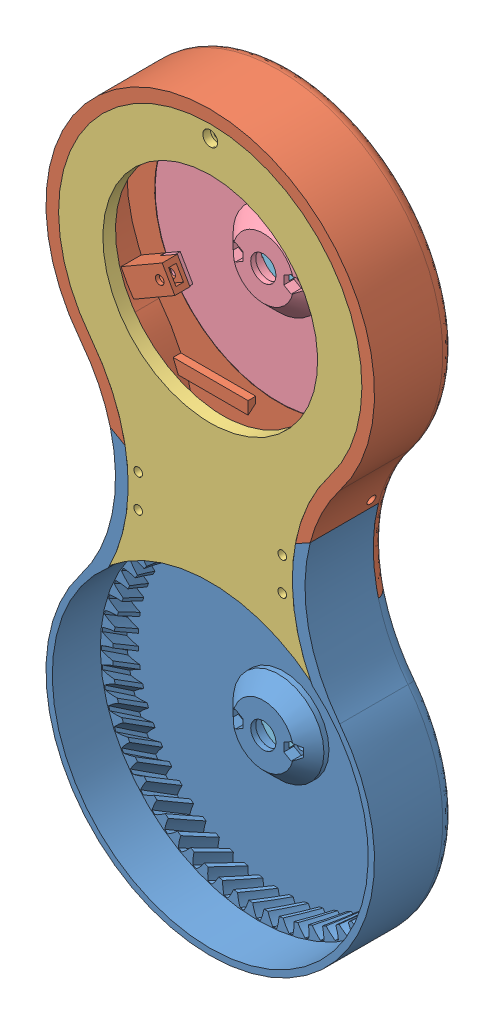
SolidWorks assembly ART2_1, configuration Predeterminado. Lengths in mm.
Overall size (130 290 32.44).
6 component instances, 5 part files, 32 mates.
Components (placement in the parent):
- Art2BodyA_Splitted_A-1: Art2BodyA_Splitted_A [Predeterminado] at (-59.4369 13.7484 145.2842) size (130 161.27 32)
- Art2BodyA_Splitted_B-1: Art2BodyA_Splitted_B [Predeterminado] at (-59.4369 93.7484 145.2842) x (1 0 0) z (0 -1 0) size (130 32.44 161.71)
- Art2BodyACover2-1: Art2BodyACover2 [Predeterminado] at (-59.4369 13.7484 177.2842) x (-1 0 0) z (0 -1 0) size (120 7 171.15)
- Art2BodyAWindow-1: Art2BodyAWindow [Predeterminado] at (-59.4369 173.7484 145.2842) x (-1 0 0) z (0 1 0) size (97.6 11 97.6)
- CommonBearingFix-1: CommonBearingFix [Predeterminado] at (-59.4369 173.7484 149.2842) x (1 0 0) z (0 0 -1) size (30 15.8 4)
- CommonBearingFix-2: CommonBearingFix [Predeterminado] at (-59.4369 13.7484 149.2842) x (1 0 0) z (0 0 -1) size (30 15.8 4)
Mates (geometry in assembly coordinates):
- Concéntrica1: concentric aligned: cylinder of Art2BodyA_Splitted_A-1 through (-87.9369 100.2484 145.2842) axis (0 0 -1) radius 1.7; cylinder of Art2BodyA_Splitted_B-1 through (-87.9369 100.2484 156.7842) axis (0 0 -1) radius 1.7
- Concéntrica2: concentric aligned: cylinder of Art2BodyA_Splitted_A-1 through (-30.9369 87.2484 145.2842) axis (0 0 -1) radius 1.7; cylinder of Art2BodyA_Splitted_B-1 through (-30.9369 87.2484 148.1842) axis (0 0 -1) radius 2.95
- Coincidente1: coincident anti-aligned: plane of Art2BodyA_Splitted_A-1 through (-59.4369 102.6007 150.2842) normal (0 0 -1); plane of Art2BodyA_Splitted_B-1 through (-8.2022 53.7484 150.2842) normal (0 0 1)
- Concéntrica5: concentric aligned: cylinder of Art2BodyA_Splitted_B-1 through (-98.4081 151.2484 150.2842) axis (0 0 1) radius 1.7; cylinder of hexagon nut_3_jis-1 through (-98.4081 151.2484 153.7842) axis (0 0 1) radius 1.25
- Paralelo5: parallel aligned: plane of Art2BodyA_Splitted_B-1 through (-98.4081 154.5984 156.7842) normal (0.5 -0.866025 0); plane of hexagon nut_3_jis-1 through (-98.4081 148.073 153.7842) normal (0.5 -0.866025 0)
- Coincidente11: coincident anti-aligned: plane of Art2BodyA_Splitted_B-1 through (9.8451 213.7484 153.7842) normal (0 0 1); plane of hexagon nut_3_jis-1 through (-103.9081 151.2484 153.7842) normal (0 0 -1)
- Concéntrica22: concentric aligned: cylinder of Art2BodyA_Splitted_B-1 through (-59.4369 173.7484 150.2842) axis (0 0 1) radius 60; cylinder of Art2BodyACover2-1 through (-59.4369 173.7484 172.2842) axis (0 0 1) radius 42.5
- Coincidente31: coincident aligned: plane of Art2BodyA_Splitted_B-1 through (-8.2022 53.7484 177.2842) normal (0 0 1); plane of Art2BodyACover2-1 through (-110.6718 53.7486 177.2842) normal (0 0 1)
- Concéntrica23: concentric aligned: cylinder of Art2BodyA_Splitted_A-1 through (-30.9369 87.2484 145.2842) axis (0 0 -1) radius 1.7; cylinder of Art2BodyACover2-1 through (-30.9369 87.2484 191.2842) axis (0 0 -1) radius 1.7
- Concéntrica25: concentric anti-aligned: cylinder of Art2BodyAWindow-1 through (-48.4369 173.7484 162.2842) axis (0 0 -1) radius 1.7; cylinder of hexagon nut_3_jis-9 through (-48.4369 173.7484 152.2842) axis (0 0 1) radius 1.25
- Concéntrica26: concentric anti-aligned: cylinder of Art2BodyAWindow-1 through (-70.4369 173.7484 162.2842) axis (0 0 -1) radius 1.7; cylinder of hexagon nut_3_jis-10 through (-70.4369 173.7484 152.2842) axis (0 0 1) radius 1.25
- Paralelo9: parallel aligned: plane of Art2BodyAWindow-1 through (-73.3381 175.4234 152.2842) normal (1 0 0); plane of hexagon nut_3_jis-10 through (-67.6869 175.3361 152.2842) normal (1 0 0)
- Coincidente34: coincident anti-aligned: plane of Art2BodyAWindow-1 through (-59.4369 173.7484 152.2842) normal (0 0 1); plane of hexagon nut_3_jis-10 through (-75.9369 173.7484 152.2842) normal (0 0 -1)
- Paralelo10: parallel aligned: plane of Art2BodyAWindow-1 through (-51.3381 175.4234 152.2842) normal (1 0 0); plane of hexagon nut_3_jis-9 through (-45.6869 175.3361 152.2842) normal (1 0 0)
- Coincidente36: coincident anti-aligned: plane of Art2BodyAWindow-1 through (-59.4369 173.7484 152.2842) normal (0 0 1); plane of hexagon nut_3_jis-9 through (-53.9369 173.7484 152.2842) normal (0 0 -1)
- Coincidente37: coincident anti-aligned: plane of Art2BodyA_Splitted_B-1 through (-64.4369 222.7484 152.2842) normal (0 0 -1); plane of Art2BodyAWindow-1 through (-59.4369 173.7484 152.2842) normal (0 0 1)
- Concéntrica29: concentric anti-aligned: cylinder of Art2BodyA_Splitted_B-1 through (-59.4369 173.7484 150.2842) axis (0 0 -1) radius 49; cylinder of Art2BodyAWindow-1 through (-59.4369 173.7484 166.3939) axis (0 0 1) radius 8.2
- Concéntrica30: concentric anti-aligned: circle of Art2BodyA_Splitted_B-1; cylinder of Art2BodyAWindow-1 through (-20.4658 151.2484 143.2842) axis (0 0 1) radius 1.7
- Concéntrica31: concentric anti-aligned: cylinder of Art2BodyAWindow-1 through (-20.4658 151.2484 143.2842) axis (0 0 1) radius 1.7; cylinder of socket head cap screw_am-4 through (-20.4658 151.2484 113.5342) axis (0 0 -1) radius 1.5
- Concéntrica32: concentric anti-aligned: cylinder of Art2BodyAWindow-1 through (-59.4369 218.7484 143.2842) axis (0 0 1) radius 1.7; cylinder of socket head cap screw_am-5 through (-59.4369 218.7484 113.5342) axis (0 0 -1) radius 1.5
- Concéntrica33: concentric anti-aligned: cylinder of Art2BodyAWindow-1 through (-98.4081 151.2484 143.2842) axis (0 0 1) radius 1.7; cylinder of socket head cap screw_am-6 through (-98.4081 151.2484 113.5342) axis (0 0 -1) radius 1.5
- Coincidente39: coincident aligned: circle of socket head cap screw_am-4; plane of socket head cap screw_am-6 through (-98.4081 151.2484 145.2842) normal (0 0 -1)
- Coincidente40: coincident aligned: plane of socket head cap screw_am-4 through (-20.4658 151.2484 145.2842) normal (0 0 -1); plane of socket head cap screw_am-5 through (-59.4369 218.7484 145.2842) normal (0 0 -1)
- Coincidente41: coincident anti-aligned: plane of Art2BodyAWindow-1 through (-59.4369 218.7484 148.2842) normal (0 0 -1); plane of socket head cap screw_am-5 through (-56.6954 218.533 148.2842) normal (0 0 1)
- Concéntrica36: concentric aligned: cylinder of Art2BodyAWindow-1 through (-48.4369 173.7484 162.2842) axis (0 0 -1) radius 1.7; cylinder of CommonBearingFix-1 through (-48.4369 173.7484 149.2842) axis (0 0 -1) radius 1.7
- Concéntrica37: concentric aligned: cylinder of Art2BodyAWindow-1 through (-70.4369 173.7484 162.2842) axis (0 0 -1) radius 1.7; cylinder of CommonBearingFix-1 through (-70.4369 173.7484 149.2842) axis (0 0 -1) radius 1.7
- Coincidente42: coincident aligned: plane of Art2BodyAWindow-1 through (-108.2369 173.7484 145.2842) normal (0 0 -1); plane of CommonBearingFix-1 through (-59.4369 173.7484 145.2842) normal (0 0 -1)
- Concéntrica39: concentric anti-aligned: cylinder of Art2BodyA_Splitted_A-1 through (-48.4369 13.7484 156.2842) axis (0 0 1) radius 1.7; cylinder of CommonBearingFix-2 through (-48.4369 13.7484 148.2842) axis (0 0 -1) radius 2.95
- Concéntrica40: concentric anti-aligned: cylinder of Art2BodyA_Splitted_A-1 through (-70.4369 13.7484 156.2842) axis (0 0 1) radius 1.7; cylinder of CommonBearingFix-2 through (-70.4369 13.7484 148.2842) axis (0 0 -1) radius 2.95
- Coincidente44: coincident aligned: plane of Art2BodyA_Splitted_A-1 through (-59.4369 93.7484 145.2842) normal (0 0 -1); plane of CommonBearingFix-2 through (-59.4369 13.7484 145.2842) normal (0 0 -1)
- Concéntrica42: concentric aligned: cylinder of Art2BodyAWindow-1 through (-70.4369 173.7484 162.2842) axis (0 0 -1) radius 1.7; cylinder of socket head cap screw_am-7 through (-70.4369 173.7484 113.5342) axis (0 0 -1) radius 1.5
- Coincidente45: coincident anti-aligned: plane of socket head cap screw_am-7 through (-71.4903 176.2886 148.2842) normal (0 0 1); plane of CommonBearingFix-1 through (-70.4369 173.7484 148.2842) normal (0 0 -1)
